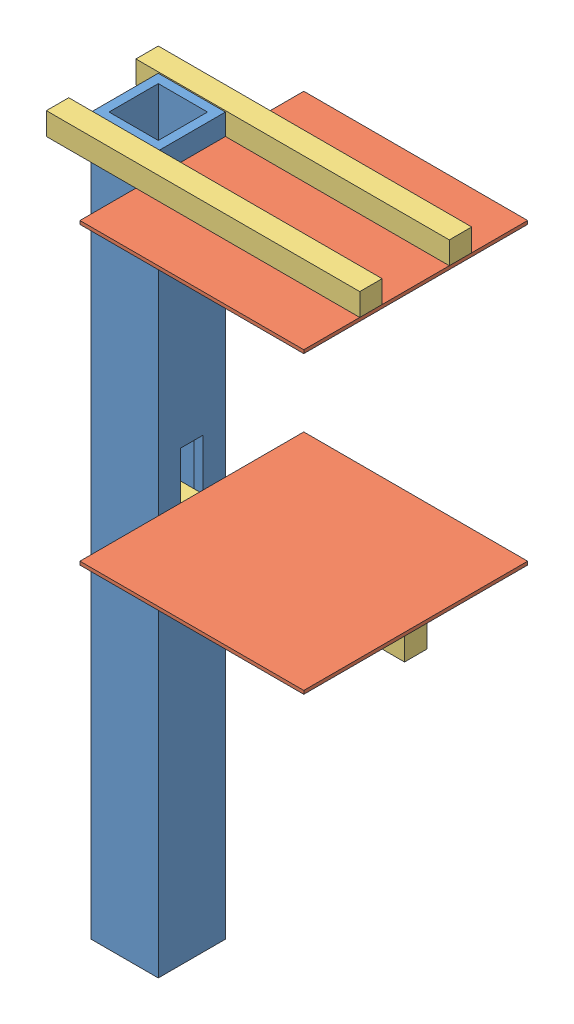
SolidWorks assembly 10 - Retrieval Arm, configuration Default. Lengths in mm.
Overall size (70 160.27 50).
6 component instances, 3 part files, 15 mates.
Components (placement in the parent):
- Main Boom-1: Main Boom [Default] at (-3.3208 -99.2527 16.6762) size (15 160 15)
- Pressure Plate-1: Pressure Plate [Default] at (11.6792 -10.6368 34.1762) x (0 -1 0) z (0 0 1) size (0.76 50 50)
- Pressure Plate-2: Pressure Plate [Default] at (11.6792 55.2589 34.1762) x (0 -1 0) z (0 0 1) size (0.76 50 50)
- Plate Key-1: Plate Key [Default] at (-8.3208 -10.6368 6.6762) x (0 -1 0) z (0 0 1) size (5 70 5)
- Plate Key-2: Plate Key [Default] at (-8.3208 61.0189 -3.3238) x (0 -1 0) z (0 0 1) size (5 70 5)
- Plate Key-3: Plate Key [Default] at (61.6792 56.0189 16.6762) x (0 1 0) z (0 0 1) size (5 70 5)
Mates (geometry in assembly coordinates):
- Parallel3: parallel anti-aligned: plane of Main Boom-1 through (-3.3208 0.7473 11.6762) normal (0 -1 0); plane of Pressure Plate-1 through (11.6792 -9.8768 34.1762) normal (0 1 0)
- Coincident4: coincident anti-aligned: plane of Main Boom-1 through (11.6792 60.7473 16.6762) normal (1 0 0); plane of Pressure Plate-1 through (11.6792 -9.8768 34.1762) normal (-1 0 0)
- Coincident5: coincident anti-aligned: plane of Main Boom-1 through (11.6792 60.7473 16.6762) normal (1 0 0); plane of Pressure Plate-2 through (11.6792 56.0189 34.1762) normal (-1 0 0)
- Width1: width anti-aligned: plane of Pressure Plate-1 through (11.6792 -9.8768 34.1762) normal (0 0 1); plane of Pressure Plate-1 through (11.6792 -9.8768 -15.8238) normal (0 0 -1); plane of Main Boom-1 through (-3.3208 60.7473 1.6762) normal (0 0 -1); plane of Main Boom-1 through (-3.3208 60.7473 16.6762) normal (0 0 1)
- Width2: width anti-aligned: plane of Pressure Plate-2 through (11.6792 56.0189 -15.8238) normal (0 0 -1); plane of Pressure Plate-2 through (11.6792 56.0189 34.1762) normal (0 0 1); plane of Main Boom-1 through (-3.3208 60.7473 16.6762) normal (0 0 1); plane of Main Boom-1 through (-3.3208 60.7473 1.6762) normal (0 0 -1)
- Coincident6: coincident anti-aligned: plane of Pressure Plate-1 through (11.6792 -10.6368 34.1762) normal (0 -1 0); plane of Plate Key-1 through (61.6792 -10.6368 6.6762) normal (0 1 0)
- Coincident7: coincident anti-aligned: plane of Main Boom-1 through (-3.3208 0.7473 6.6762) normal (0 0 1); plane of Plate Key-1 through (61.6792 -10.6368 6.6762) normal (0 0 -1)
- Coincident8: coincident aligned: plane of Pressure Plate-1 through (61.6792 -9.8768 34.1762) normal (1 0 0); plane of Plate Key-1 through (61.6792 -10.6368 6.6762) normal (1 0 0)
- Coincident9: coincident anti-aligned: plane of Main Boom-1 through (-3.3208 60.7473 1.6762) normal (0 0 -1); plane of Plate Key-2 through (61.6792 61.0189 1.6762) normal (0 0 1)
- Coincident10: coincident anti-aligned: plane of Plate Key-2 through (61.6792 56.0189 -3.3238) normal (0 -1 0); plane of Pressure Plate-2 through (11.6792 56.0189 34.1762) normal (0 1 0)
- Coincident11: coincident aligned: plane of Pressure Plate-2 through (61.6792 56.0189 34.1762) normal (1 0 0); plane of Plate Key-2 through (61.6792 61.0189 -3.3238) normal (1 0 0)
- Coincident12: coincident anti-aligned: plane of Plate Key-3 through (-8.3208 56.0189 16.6762) normal (0 -1 0); plane of Pressure Plate-2 through (11.6792 56.0189 34.1762) normal (0 1 0)
- Coincident13: coincident anti-aligned: plane of Main Boom-1 through (-3.3208 60.7473 16.6762) normal (0 0 1); plane of Plate Key-3 through (-8.3208 56.0189 16.6762) normal (0 0 -1)
- Coincident14: coincident aligned: plane of Pressure Plate-2 through (61.6792 56.0189 34.1762) normal (1 0 0); plane of Plate Key-3 through (61.6792 56.0189 16.6762) normal (1 0 0)
- LimitDistance1: limit distance = 13.6159 mm anti-aligned: plane of Main Boom-1 through (-3.3208 -29.2527 11.6762) normal (0 1 0); plane of Plate Key-1 through (61.6792 -15.6368 6.6762) normal (0 -1 0)
